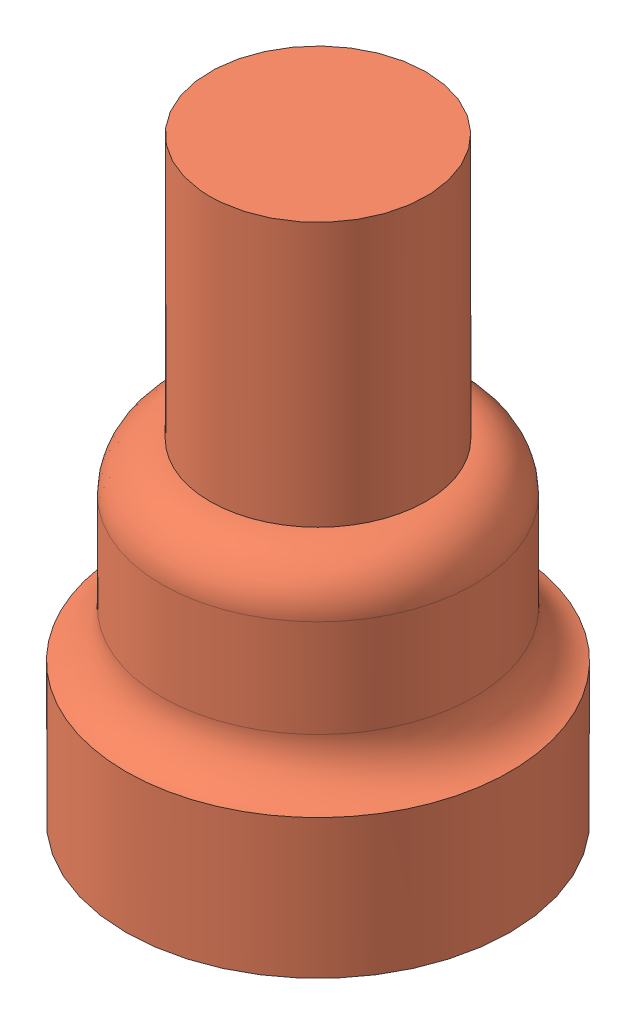
SolidWorks assembly Button_Cap_Test, configuration Default. Lengths in mm.
Overall size (16 26.3 16).
2 component instances, 2 part files, 2 mates.
Components (placement in the parent):
- Button-1: Button [Default] at (-4.8487 0.7695 2.0358) size (12 14.3 12)
- Button_Cap-1: Button_Cap [Default] at (-4.8487 -5.0305 2.0358) size (16 24.8 16)
Mates (geometry in assembly coordinates):
- Coincident1: coincident anti-aligned: plane of Button-1 through (-4.8487 7.7695 2.0358) normal (0 1 0); plane of Button_Cap-1 through (-4.8487 7.7695 2.0358) normal (0 -1 0)
- Coincident2: coincident anti-aligned: circle of Button-1; circle of Button_Cap-1
